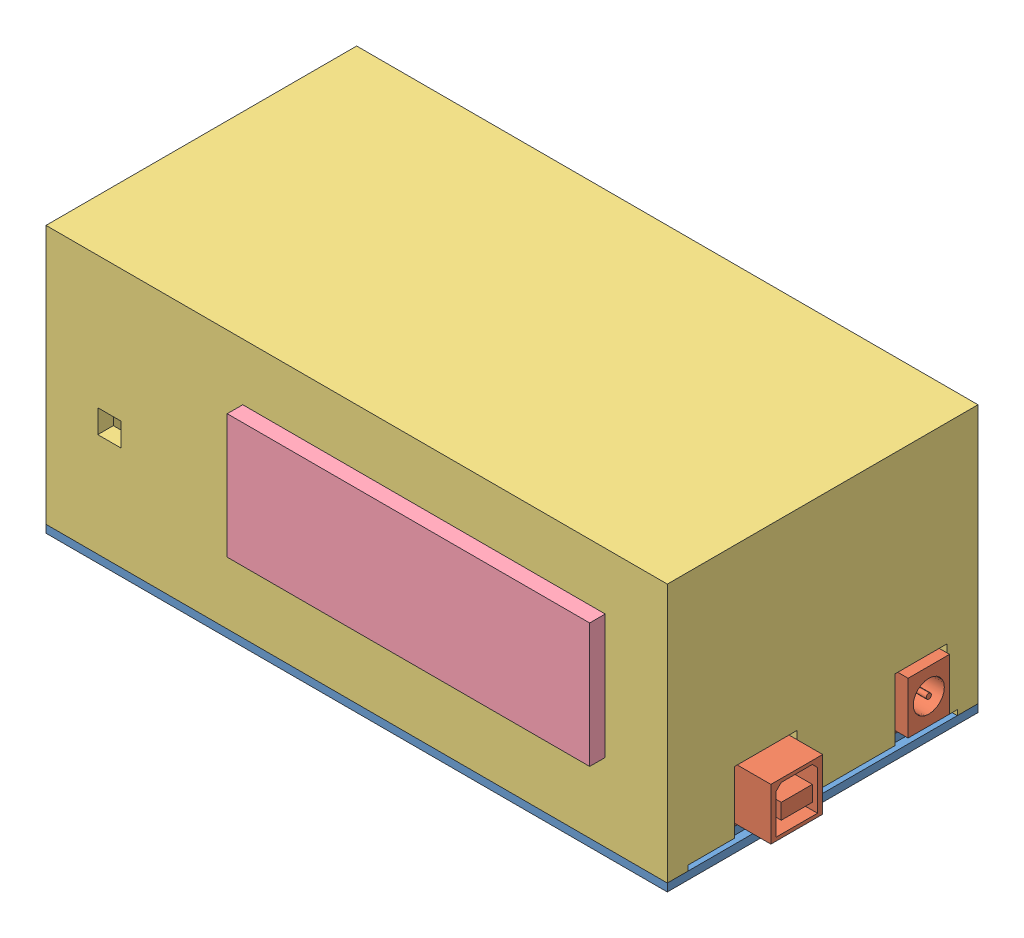
SolidWorks assembly arduino kutusu, configuration Default. Lengths in mm.
Overall size (126 51.5 63).
4 component instances, 4 part files, 10 mates.
Components (placement in the parent):
- kapak-1: kapak [Default] at (41.174 49.0608 103.2335) size (120 3 60)
- Arduino-1: Arduino [Default] at (65.674 52.0608 103.2335) x (-1 0 0) z (0 0 -1) size (75.5 11 52)
- box-1: box [Default] at (41.174 50.5608 103.2335) size (120 50 60)
- LCD-1: LCD [Default] at (54.174 77.5608 129.2335) size (80 35 11)
Mates (geometry in assembly coordinates):
- Coincident1: coincident anti-aligned: plane of kapak-1 through (41.174 52.0608 103.2335) normal (0 1 0); plane of Arduino-1 through (65.674 52.0608 103.2335) normal (0 -1 0)
- Parallel1: parallel aligned: plane of kapak-1 through (-18.826 52.0608 133.2335) normal (0 0 1); plane of Arduino-1 through (99.674 53.0608 129.2335) normal (0 0 1)
- Coincident3: coincident aligned: plane of kapak-1 through (99.674 50.5608 74.7335) normal (1 0 0); plane of Arduino-1 through (99.674 53.0608 77.2335) normal (1 0 0)
- Width1: width anti-aligned: plane of Arduino-1 through (99.674 53.0608 129.2335) normal (0 0 1); plane of kapak-1 through (99.674 53.0608 77.2335) normal (0 0 -1); plane of Arduino-1 through (-18.826 52.0608 73.2335) normal (0 0 -1); plane of kapak-1 through (-18.826 52.0608 133.2335) normal (0 0 1)
- Coincident4: coincident aligned: plane of kapak-1 through (-18.826 52.0608 133.2335) normal (0 0 1); plane of box-1 through (-18.826 100.5608 133.2335) normal (0 0 1)
- Coincident5: coincident aligned: plane of kapak-1 through (101.174 52.0608 73.2335) normal (1 0 0); plane of box-1 through (101.174 100.5608 133.2335) normal (1 0 0)
- Coincident7: coincident anti-aligned: plane of kapak-1 through (41.174 50.5608 103.2335) normal (0 1 0); plane of box-1 through (41.174 50.5608 103.2335) normal (0 -1 0)
- Coincident8: coincident anti-aligned: plane of box-1 through (19.174 89.5608 126.2335) normal (0 -1 0); plane of LCD-1 through (19.174 89.5608 136.2335) normal (0 1 0)
- Coincident9: coincident anti-aligned: plane of box-1 through (89.174 89.5608 126.2335) normal (-1 0 0); plane of LCD-1 through (89.174 89.5608 136.2335) normal (1 0 0)
- Coincident10: coincident anti-aligned: plane of box-1 through (-15.826 97.5608 130.2335) normal (0 0 -1); plane of LCD-1 through (54.174 77.5608 130.2335) normal (0 0 1)
